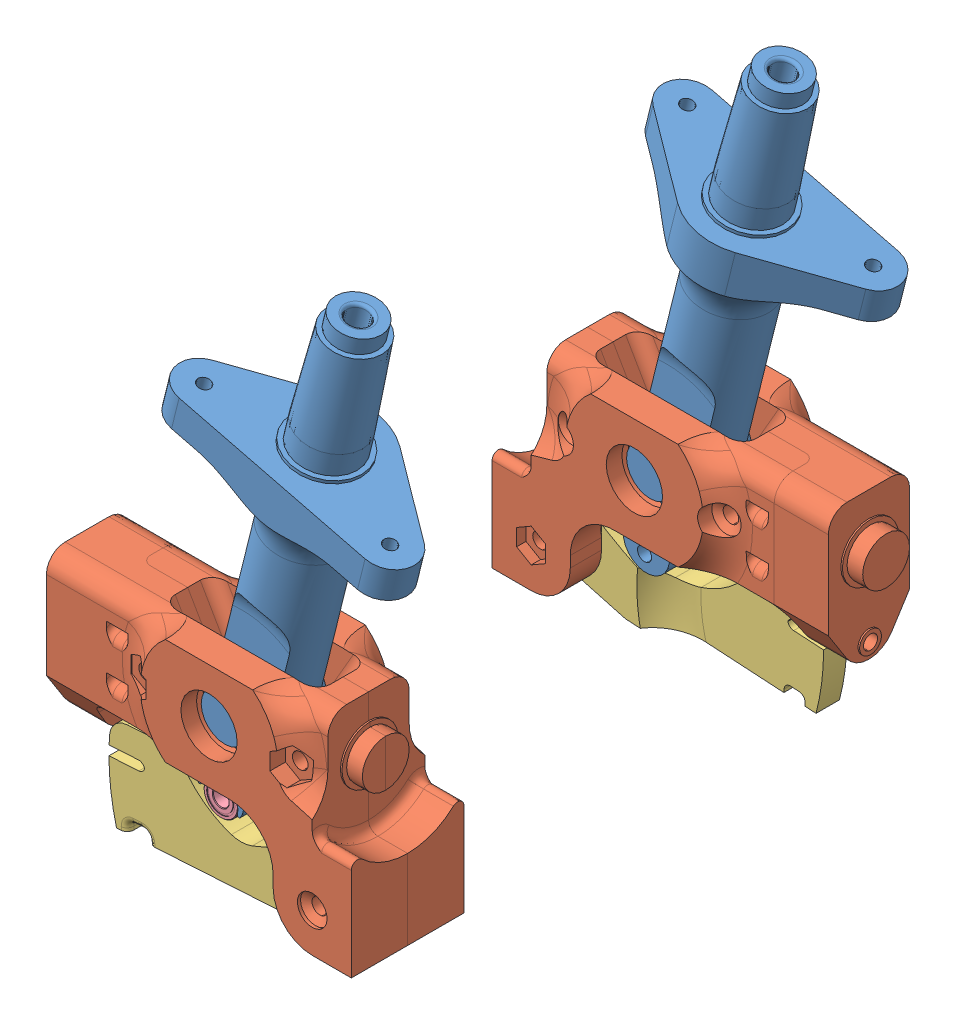
SolidWorks assembly Roll Assembly, configuration Default. Lengths in mm.
Overall size (129.78 182.54 175.02).
8 component instances, 4 part files, 19 mates.
Components (placement in the parent):
- Center Core-1: Center Core [Default] at (-8.4579 -33.9627 0) x (-0.970362 0.241655 0) z (0 0 -1) size (77.28 158.27 34.47)
- Axis B Block-1: Axis B Block [Default] at origin size (108 64.09 38.74)
- CAM Roll-1: CAM Roll [Default] at (-33 -34.5 0) x (-0.998182 0.060277 0) z (0 0 -1) size (85.5 30 15.96)
- Bearing-1: Bearing [685] at (-7.2497 -29.1109 -4.5) x (0 0 -1) z (0.305655 0.952142 0) size (5 11 11)
- Center Core-4: Center Core [Default] at (-8.4579 -33.9627 136) x (0.970362 -0.241655 0) z (0 0 1) size (77.28 158.27 34.47)
- Axis B Block-3: Axis B Block [Default] at (0 0 136) x (-1 0 0) z (0 0 -1) size (108 64.09 38.74)
- CAM Roll-3: CAM Roll [Default] at (33 -34.5 136) x (0.998135 0.061038 0) z (0 0 1) size (85.5 30 15.96)
- Bearing-3: Bearing [685] at (-7.2497 -29.1109 140.5) x (0 0 1) z (-1 0 0) size (5 11 11)
Mates (geometry in assembly coordinates):
- Coincident1: coordinate: point of Axis B Block-1
- Concentric2: concentric anti-aligned: cylinder of Axis B Block-1 through (-33 -34.5 13) axis (0 0 -1) radius 2.5; cylinder of CAM Roll-1 through (-33 -34.5 -13) axis (0 0 1) radius 3
- Distance2: distance = 0.5 mm anti-aligned: plane of CAM Roll-1 through (-33 -34.5 -7.5) normal (0 0 -1); plane of Axis B Block-1 through (0 0 -8) normal (0 0 1)
- Concentric3: concentric anti-aligned: cylinder of Center Core-1 through (-7.2497 -29.1109 12) axis (0 0 -1) radius 2.25; cylinder of Bearing-1 through (-7.2497 -29.1109 5.0787) axis (0 0 1) radius 2.5
- Concentric4: concentric anti-aligned: cylinder of Center Core-1 through (0 0 -13) axis (0 0 1) radius 7.5; cylinder of Axis B Block-1 through (0 0 13) axis (0 0 -1) radius 9
- Coincident4: coincident anti-aligned: plane of Center Core-1 through (0 0 -8) normal (0 0 -1); plane of Axis B Block-1 through (0 0 -8) normal (0 0 1)
- PathMate2: path: point of Bearing-1; curve of CAM Roll-1; curve of CAM Roll-1
- LimitAngle1: limit planar angle = 0.244071 rad anti-aligned: plane of Center Core-1 through (-8.4579 -33.9627 0) normal (-0.970362 0.241655 0)
- Coincident6: coincident anti-aligned: plane of Center Core-4 through (0 0 128) normal (0 0 -1); plane of Axis B Block-3 through (0 0 128) normal (0 0 1)
- Distance3: distance = 100 mm anti-aligned: plane of Axis B Block-3 through (33 -34.5 118) normal (0 0 -1); plane of Axis B Block-1 through (-33 -34.5 18) normal (0 0 1)
- Coincident8: coincident aligned: plane of Axis B Block-1 through (-33 17 13) normal (0 1 0); plane of Axis B Block-3 through (33 17 123) normal (0 1 0)
- Concentric5: concentric anti-aligned: cylinder of Axis B Block-1 through (0 0 13) axis (0 0 -1) radius 9; cylinder of Axis B Block-3 through (0 0 123) axis (0 0 1) radius 9
- Concentric6: concentric anti-aligned: cylinder of Center Core-4 through (0 0 149) axis (0 0 -1) radius 7.5; cylinder of Axis B Block-3 through (0 0 123) axis (0 0 1) radius 9
- Coincident9: coincident anti-aligned: plane of Center Core-1 through (-8.4579 -33.9627 0) normal (-0.970362 0.241655 0); plane of Center Core-4 through (-8.4579 -33.9627 136) normal (0.970362 -0.241655 0)
- Coincident10: coincident anti-aligned: plane of Axis B Block-3 through (33 -34.5 143.5) normal (0 0 -1); plane of CAM Roll-3 through (33 -34.5 143.5) normal (0 0 1)
- Concentric7: concentric anti-aligned: cylinder of Axis B Block-3 through (33 -34.5 123) axis (0 0 1) radius 2.5; cylinder of CAM Roll-3 through (33 -34.5 149) axis (0 0 -1) radius 3
- Concentric8: concentric anti-aligned: cylinder of Center Core-4 through (-7.2497 -29.1109 124) axis (0 0 1) radius 2.25; cylinder of Bearing-3 through (-7.2497 -29.1109 130.9213) axis (0 0 -1) radius 2.5
- Coincident11: coincident anti-aligned: plane of Center Core-4 through (-7.2497 -29.1109 138) normal (0 0 1); plane of Bearing-3 through (-7.2497 -25.2109 138) normal (0 0 -1)
- PathMate3: path: point of Bearing-3; curve of CAM Roll-3; curve of CAM Roll-3
